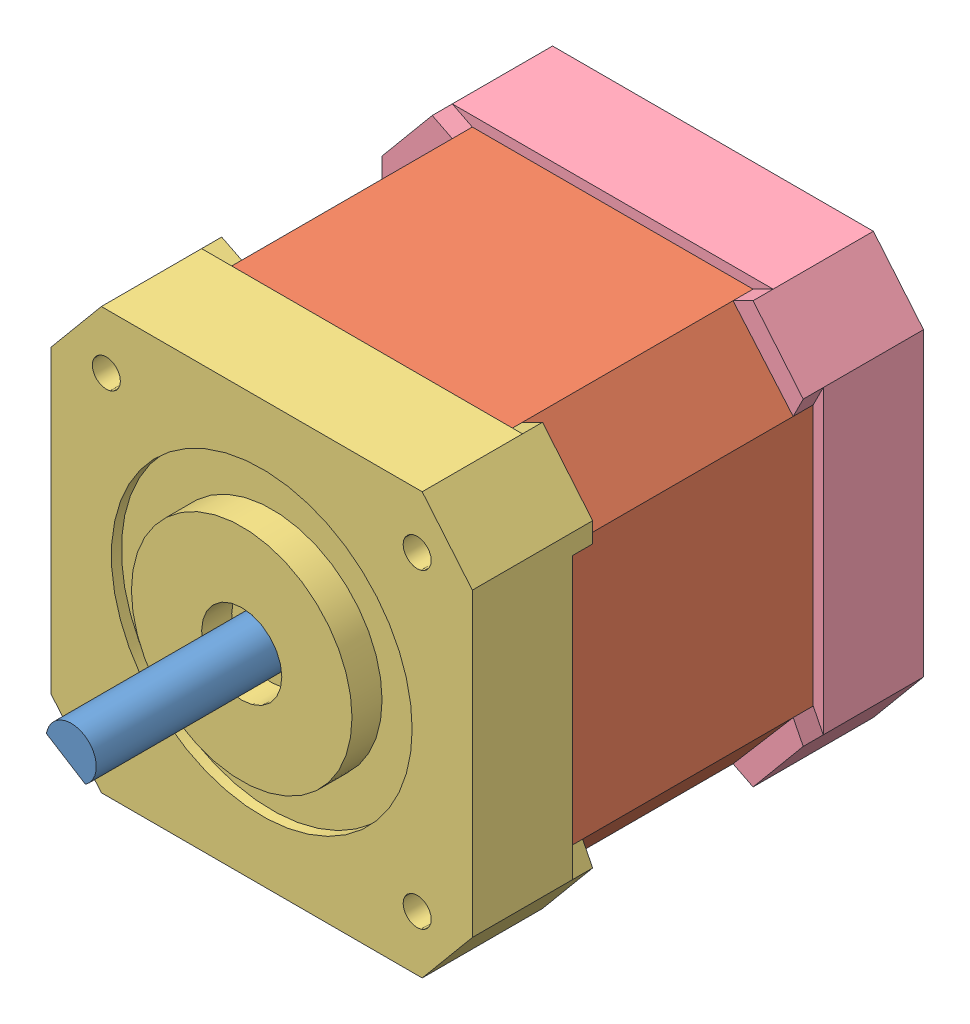
SolidWorks assembly Nema 17, configuration Predeterminado. Lengths in mm.
Overall size (42 42 64).
4 component instances, 4 part files, 6 mates.
Components (placement in the parent):
- flecha-1: flecha [Predeterminado] at (-20.4936 5.5864 32.5) x (-0.847996 0.530003 0) z (0 0 1) size (5 5 24)
- rotor-1: rotor [Predeterminado] at (-20.4936 5.2638 0.5) size (40 40 29)
- Tapa motor-1: Tapa motor [Predeterminado] at (-20.4936 5.5864 37.5) x (-1 0 0) z (0 0 -1) size (42 42 14)
- Base motor-1: Base motor [Predeterminado] at (-20.4936 5.5864 -7.5) size (42 42 12)
Mates (geometry in assembly coordinates):
- Coincidente2: coincident: rotor-1, Base motor-1
- Coincidente3: coincident: rotor-1, Base motor-1
- Coincidente4: coincident: rotor-1, Tapa motor-1
- Coincidente5: coincident: rotor-1, Tapa motor-1
- Coincidente6: coincident: flecha-1, Tapa motor-1
- Coincidente7: coincident: Tapa motor-1, Base motor-1
